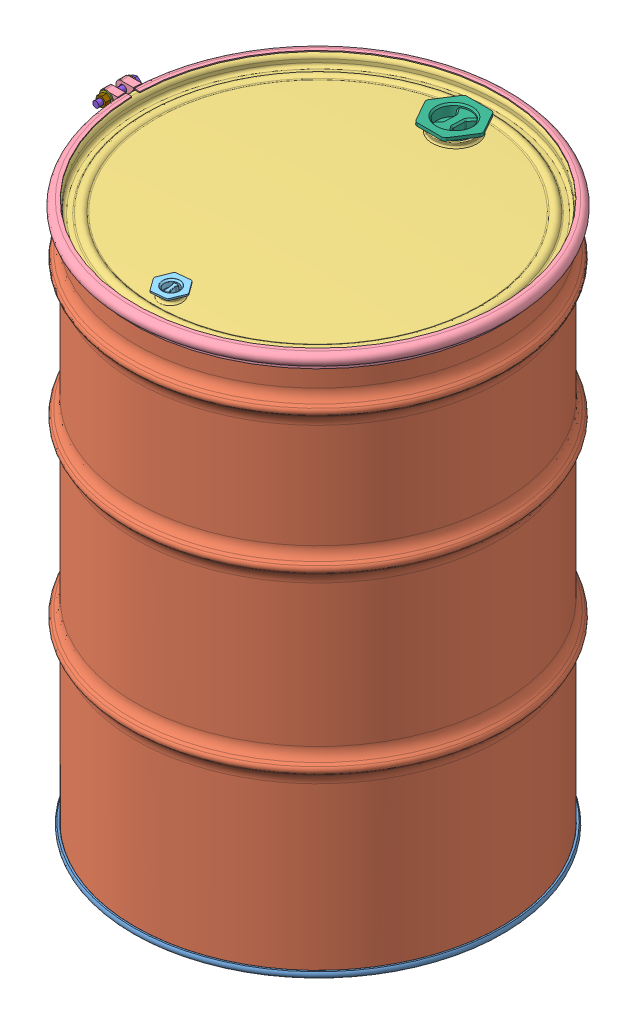
SolidWorks assembly 55GallonDrum, configuration Default. Lengths in mm.
Overall size (625.38 863.57 603.05).
11 component instances, 10 part files, 26 mates.
Components (placement in the parent):
- DrumImport-1: DrumImport [Default] at origin size (606.91 955.45 609.87) (hidden)
- Bottom-1: Bottom [Default] at origin size (584.06 21.69 584.06)
- Cylinder-2: Cylinder [Default] at origin size (598.84 849.75 598.84)
- Lid-1: Lid [Default] at origin size (598.96 20.09 598.96)
- Clamp-1: Clamp [Default] at origin size (625.38 26.08 603.05)
- _.75''pipePlug-1: _.75''pipePlug [default] at (0 395.8736 230.8144) x (0.995167 0.003578 -0.098136) z (0 0.999336 0.036434) size (49.18 43.52 18.81)
- _2''pipePlug-1: _2''pipePlug [default] at (0 401.2642 -214.0752) x (1 0 0) z (0 0.999341 -0.036296) size (88.16 78.09 28.78)
- FW.38SAE-1: FW.38SAE [Default] at (-312.7375 391.4227 -19.8438) size (20.62 20.62 1.59)
- FW.38SAE-2: FW.38SAE [Default] at (-312.7375 391.4227 19.8438) x (-1 0 0) z (0 0 -1) size (20.62 20.62 1.59)
- HHCS.38-16x2.25ZpGr5t-1: HHCS.38-16x2.25ZpGr5t [Default] at (-312.7375 391.4227 -20.6375) x (-0.961637 -0.274327 0) z (0 0 -1) size (16.5 14.29 63.5)
- HN.38-16-1: HN.38-16 [Default] at (-312.7375 391.4227 20.6375) x (-0.942487 -0.334242 0) z (0 0 1) size (16.5 14.29 8.33)
Mates (geometry in assembly coordinates):
- InPlace1: in place: plane of ? through (0 0 0) normal (0 0 1); moOrthogonalPlaneRef_w of ? through (0 0 0) normal (0 1 0); plane of ? through (0 0 0) normal (1 0 0); unknown of ?
- Coincident1: coincident aligned: plane of Bottom-1; plane of assembly
- Coincident2: coincident aligned: plane of ? through (0 0 0) normal (0 1 0)
- Coincident3: coincident anti-aligned: plane of ? through (0 0 0) normal (1 0 0)
- Coincident4: coincident aligned: plane of Cylinder-2 through (0 0 0) normal (0 0 1); plane of assembly through (0 0 0) normal (0 0 1)
- Coincident5: coincident aligned: plane of Cylinder-2 through (0 0 0) normal (0 1 0); plane of assembly through (0 0 0) normal (0 1 0)
- Coincident6: coincident aligned: plane of Cylinder-2 through (0 0 0) normal (1 0 0); plane of assembly through (0 0 0) normal (1 0 0)
- InPlace2: in place: plane of ? through (0 0 0) normal (0 0 1); plane of ? through (0 0 0) normal (0 1 0); plane of ? through (0 0 0) normal (1 0 0); unknown of ?
- Coincident7: coincident aligned: plane of Lid-1; plane of assembly
- Coincident8: coincident aligned: plane of ? through (0 0 0) normal (0 1 0)
- Coincident9: coincident anti-aligned: plane of ? through (0 0 0) normal (1 0 0)
- InPlace3: in place: plane of ? through (0 0 0) normal (0 0 1); plane of ? through (0 0 0) normal (0 1 0); plane of ? through (0 0 0) normal (1 0 0); unknown of ?
- Coincident10: coincident aligned: plane of Clamp-1; plane of assembly
- Coincident11: coincident aligned: plane of ? through (0 0 0) normal (0 1 0)
- Coincident12: coincident anti-aligned: plane of ? through (0 0 0) normal (1 0 0)
- Concentric1: concentric aligned: circle of Lid-1; cylinder of _.75''pipePlug-1 through (0 388.0049 230.5275) axis (0 0.999336 0.036434) radius 11.1125
- Coincident10: coincident aligned: circle of Lid-1; plane of _.75''pipePlug-1 through (0 388.0049 230.5275) normal (0 0.999336 0.036434)
- Coincident11: coincident aligned: circle of Lid-1; plane of _2''pipePlug-1 through (0 388.5725 -213.6143) normal (0 0.999341 -0.036296)
- Concentric2: concentric aligned: circle of Lid-1; cylinder of _2''pipePlug-1 through (0 388.5725 -213.6143) axis (0 0.999341 -0.036296) radius 25.7969
- Coincident15: coincident anti-aligned: plane of Clamp-1 through (301.5269 383.4852 -19.05) normal (0 0 -1); plane of FW.38SAE-1 through (-312.7375 391.4227 -19.05) normal (0 0 1)
- Concentric3: concentric anti-aligned: cylinder of Clamp-1 through (-312.7375 391.4227 -301.5259) axis (0 0 1) radius 5.5563; cylinder of FW.38SAE-1 through (-312.7375 391.4227 -19.05) axis (0 0 -1) radius 10.3124
- Concentric4: concentric anti-aligned: cylinder of FW.38SAE-1 through (-312.7375 391.4227 -19.05) axis (0 0 -1) radius 10.3124; cylinder of FW.38SAE-2 through (-312.7375 391.4227 19.05) axis (0 0 1) radius 10.3124
- Concentric6: concentric anti-aligned: cylinder of FW.38SAE-2 through (-312.7375 391.4227 19.05) axis (0 0 1) radius 10.3124; cylinder of HN.38-16-1 through (-312.7375 391.4227 28.9719) axis (0 0 -1) radius 4.7625
- Coincident19: coincident anti-aligned: plane of FW.38SAE-2 through (-312.7375 391.4227 20.6375) normal (0 0 1); plane of HN.38-16-1 through (-312.7375 391.4227 20.6375) normal (0 0 -1)
- Concentric7: concentric: cylinder of FW.38SAE-1 through (-312.7375 391.4227 -19.05) axis (0 0 -1) radius 10.3124; cylinder of HHCS.38-16x2.25ZpGr5t-1 through (-312.7375 391.4227 36.5125) axis (0 0 -1) radius 4.7625
- Coincident20: coincident anti-aligned: plane of FW.38SAE-1 through (-312.7375 391.4227 -20.6375) normal (0 0 -1); plane of HHCS.38-16x2.25ZpGr5t-1 through (-312.7375 391.4227 -20.6375) normal (0 0 1)
